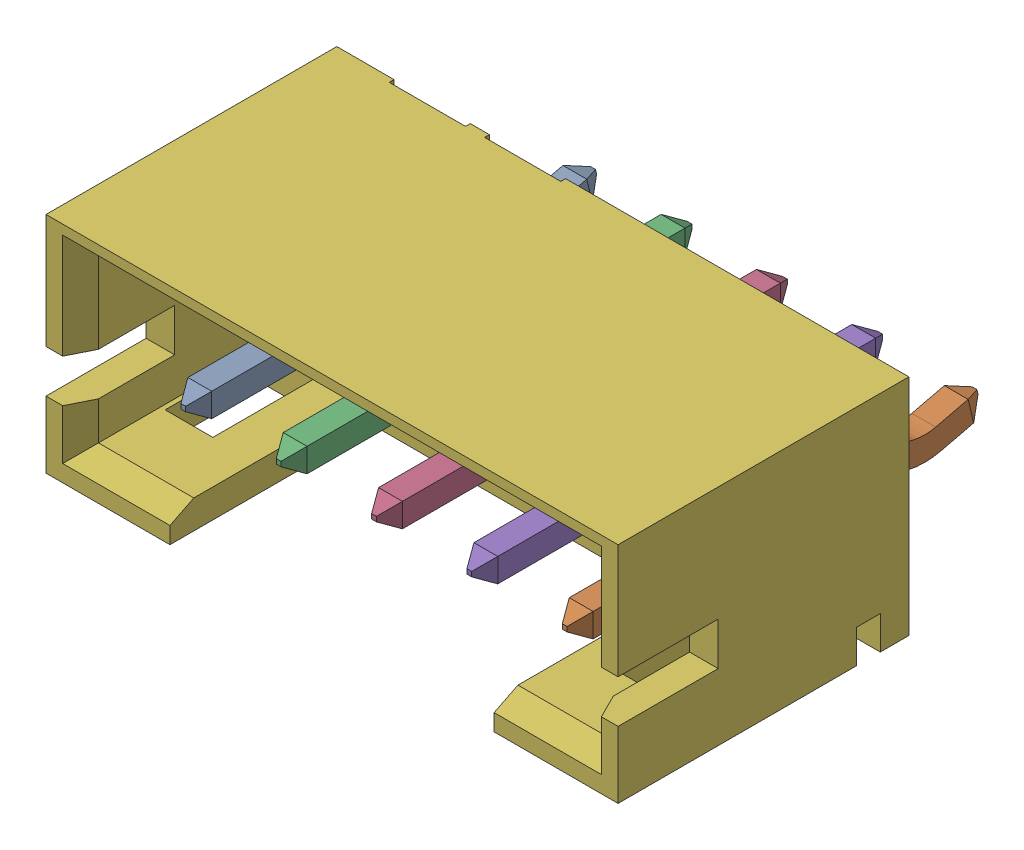
SolidWorks assembly 62000511622, configuration Default. Lengths in mm.
Overall size (12 4.7 9.5).
6 component instances, 3 part files, 0 mates.
Components (placement in the parent):
- Pin1-1: Pin1 [Default] at (-4 -0.35 -3.88) x (0 1 0) z (0 0 1) size (0.77 0.5 8.62)
- Pin1-2: Pin1 [Default] at (4 -0.35 -3.88) x (0 1 0) z (0 0 1) size (0.77 0.5 8.62)
- Pin2-1: Pin2 [Default] at (-2 -0.85 -6.45) x (0 -1 0) z (0 0 1) size (0.5 0.5 8.62)
- Pin2-2: Pin2 [Default] at (0 -0.85 -6.45) x (0 -1 0) z (0 0 1) size (0.5 0.5 8.62)
- Pin2-3: Pin2 [Default] at (2 -0.85 -6.45) x (0 -1 0) z (0 0 1) size (0.5 0.5 8.62)
- 62000511622-1: 62000511622 [Default] at origin size (12 4.7 6.1)
